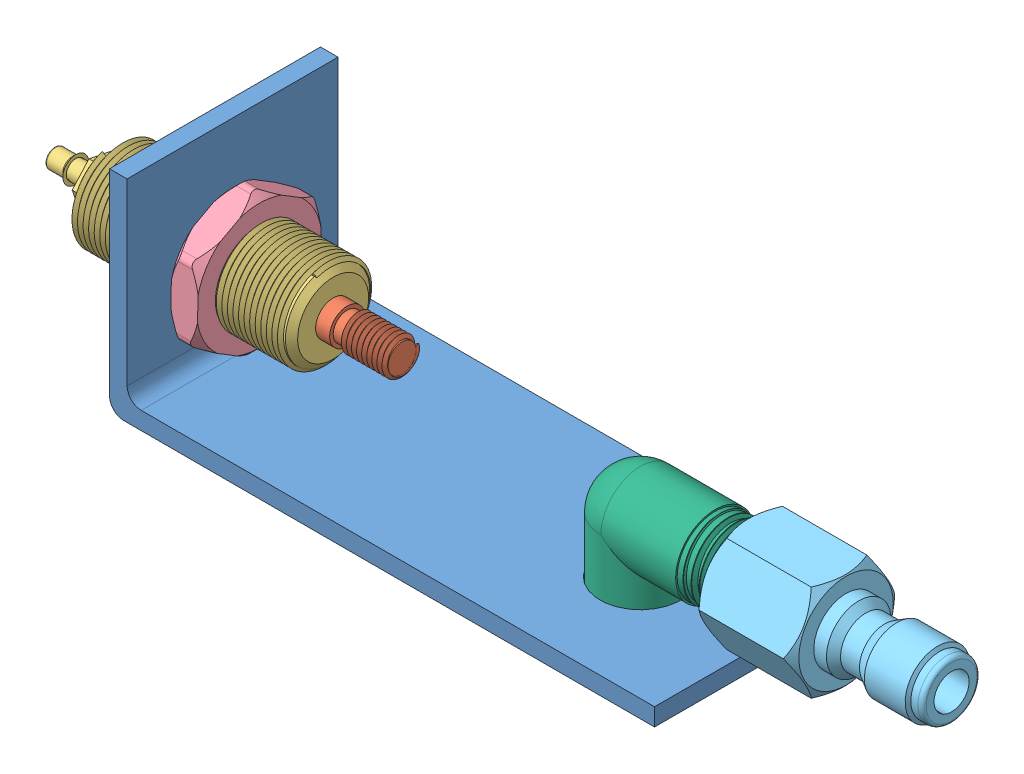
SolidWorks assembly QD assembly, configuration Default. Lengths in mm.
Overall size (161.98 50.98 38.1).
8 component instances, 7 part files, 18 mates.
Components (placement in the parent):
- Plate-1: Plate [Default] at (41.9272 42.6717 74.9889) size (98.42 38.1 38.1)
- Cover-1: Cover [Default] at (106.1892 56.0067 74.9889) x (0 0 -1) z (1 0 0) size (25.4 22.86 89.05) (hidden)
- Piston-1: Piston [Default] at (-3.0308 58.5467 74.9889) x (0 -0.964067 -0.265658) z (1 0 0) size (13.33 13.33 30.91)
- Piston Outer-1: Piston Outer [Default] at (-27.2878 58.5467 74.9889) x (0 0.949125 0.314901) z (1 0 0) size (16.52 16.52 50.29)
- Nut-1: Nut [Default] at (-8.8728 58.5467 74.9889) x (0 0.498337 -0.866984) z (-1 0 0) size (25.19 22.23 5.78)
- Nut-2: Nut [Default] at (-0.8718 58.5467 74.9889) x (0 -0.999643 0.026719) z (-1 0 0) size (25.19 22.23 5.78)
- NPT-QD Fitting-1: NPT-QD Fitting [Default] at (105.097 55.979 74.9889) x (0 -0.866025 0.5) z (-1 0 0) size (21.89 17.4 37.31)
- AN-NPT -6 elbow-1: AN-NPT -6 elbow [5482K211] at (67.9622 55.979 74.9889) x (0 1 0) z (0 0 -1) size (33.41 34.63 14.44)
Mates (geometry in assembly coordinates):
- Concentric2: concentric anti-aligned: cylinder of Piston-1 through (24.9092 58.5467 74.9889) axis (-1 0 0) radius 3.175; cylinder of Piston Outer-1 through (-12.9368 58.5467 74.9889) axis (1 0 0) radius 3.175
- Concentric4: concentric anti-aligned: cylinder of Piston Outer-1 through (12.4632 58.5467 74.9889) axis (-1 0 0) radius 7.62; cylinder of Nut-2 through (-5.6978 58.5467 74.9889) axis (1 0 0) radius 7.9375
- Concentric5: concentric anti-aligned: cylinder of Piston Outer-1 through (12.4632 58.5467 74.9889) axis (-1 0 0) radius 7.62; cylinder of Nut-1 through (-13.6988 58.5467 74.9889) axis (1 0 0) radius 7.9375
- Coincident2: coincident anti-aligned: plane of Plate-1 through (-8.8728 42.6717 74.9889) normal (-1 0 0); plane of Nut-1 through (-8.8728 58.5467 74.9889) normal (1 0 0)
- Coincident3: coincident anti-aligned: plane of Plate-1 through (-5.6978 42.6717 74.9889) normal (1 0 0); plane of Nut-2 through (-5.6978 58.5467 74.9889) normal (-1 0 0)
- Distance1: distance = 18.415 mm aligned: plane of Piston Outer-1 through (-27.2878 58.5467 74.9889) normal (-1 0 0); plane of Plate-1 through (-8.8728 42.6717 74.9889) normal (-1 0 0)
- Coincident6: coincident anti-aligned: plane of Cover-1 through (24.9092 58.5467 74.9889) normal (-1 0 0); plane of Piston-1 through (24.9092 58.5467 74.9889) normal (1 0 0)
- Concentric6: concentric anti-aligned: cylinder of Cover-1 through (24.9092 58.5467 74.9889) axis (-1 0 0) radius 2.794; cylinder of Piston-1 through (15.0032 58.5467 74.9889) axis (1 0 0) radius 2.54
- Coincident5: coincident anti-aligned: plane of Plate-1 through (41.9272 45.8467 74.9889) normal (0 1 0); plane of Cover-1 through (17.2892 45.8467 87.6889) normal (0 -1 0)
- Concentric8: concentric anti-aligned: cylinder of Plate-1 through (-8.8728 58.5467 74.9889) axis (1 0 0) radius 8.001; cylinder of Piston Outer-1 through (12.4632 58.5467 74.9889) axis (-1 0 0) radius 7.62
- Distance6: distance = 0.127 mm anti-aligned: plane of Cover-1 through (75.7092 64.8055 69.9089) normal (0 -1 0); plane of NPT-QD Fitting-1 through (87.317 64.6785 80.0116) normal (0 1 0)
- Distance3: distance = 7.62 mm anti-aligned: plane of NPT-QD Fitting-1 through (87.317 55.979 74.9889) normal (-1 0 0); plane of AN-NPT -6 elbow-1 through (94.937 55.979 74.9889) normal (1 0 0)
- Concentric9: concentric anti-aligned: cylinder of NPT-QD Fitting-1 through (103.827 55.979 74.9889) axis (-1 0 0) radius 7.112; cylinder of AN-NPT -6 elbow-1 through (81.4496 55.979 74.9889) axis (1 0 0) radius 4.5917
- Parallel6: parallel anti-aligned: cylinder of Plate-1 through (67.9622 80.7717 74.9889) axis (0 -1 0) radius 7.3025; cylinder of AN-NPT -6 elbow-1 through (67.9622 29.7916 74.9889) axis (0 1 0) radius 4.7314
- Concentric12: concentric aligned: cylinder of Plate-1 through (67.9622 80.7717 74.9889) axis (0 -1 0) radius 7.3025; cylinder of AN-NPT -6 elbow-1 through (67.9622 55.979 74.9889) axis (0 -1 0) radius 7.1374
- Parallel7: parallel aligned: plane of Cover-1 through (106.1892 56.0067 74.9889) normal (1 0 0); plane of NPT-QD Fitting-1 through (105.097 55.979 74.9889) normal (1 0 0)
- Distance4: distance = 2.54 mm aligned: plane of Piston-1 through (15.0032 58.5467 74.9889) normal (1 0 0); plane of Piston Outer-1 through (12.4632 58.5467 74.9889) normal (1 0 0)
- Distance5: distance = 15.24 mm aligned: plane of Piston Outer-1 through (12.4632 58.5467 74.9889) normal (1 0 0); plane of Piston-1 through (27.7032 58.5467 74.9889) normal (1 0 0)
